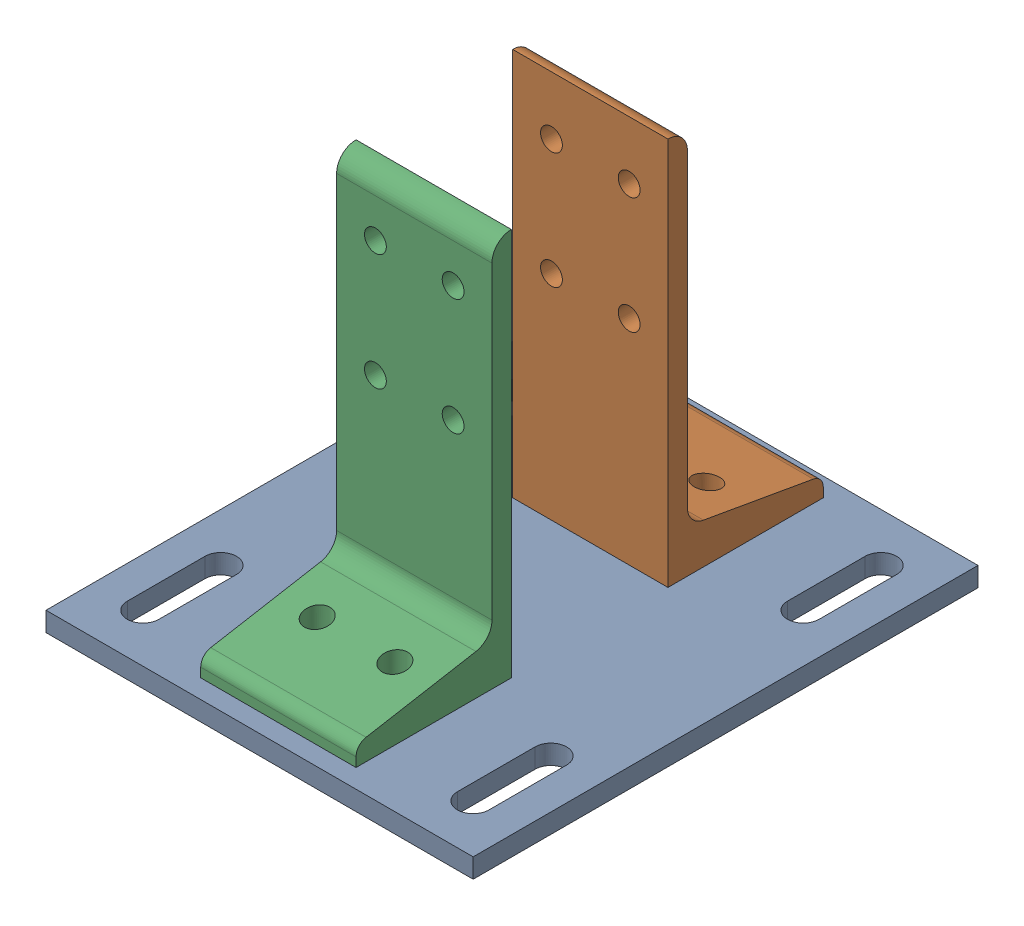
SolidWorks assembly Mirror8020-2387-DEFAULT5, configuration Default. Lengths in mm.
Overall size (139.7 133.35 165.1).
3 component instances, 2 part files, 0 mates.
Components (placement in the parent):
- Mirror8020-2387-DEFAULT_238708-1: Mirror8020-2387-DEFAULT_238708 [Default] at (-67.1549 7.3704 -27.8119) size (139.7 6.35 165.1)
- Mirror8020-2387-DEFAULT_238509-1: Mirror8020-2387-DEFAULT_238509 [Default] at (9.1264 0.0214 -49.7635) x (0 0 -1) z (1 0 0) size (50.8 127 50.8)
- Mirror8020-2387-DEFAULT_238509-2: Mirror8020-2387-DEFAULT_238509 [Default] at (-41.6736 0.0214 46.9187) x (0 0 1) z (-1 0 0) size (50.8 127 50.8)
